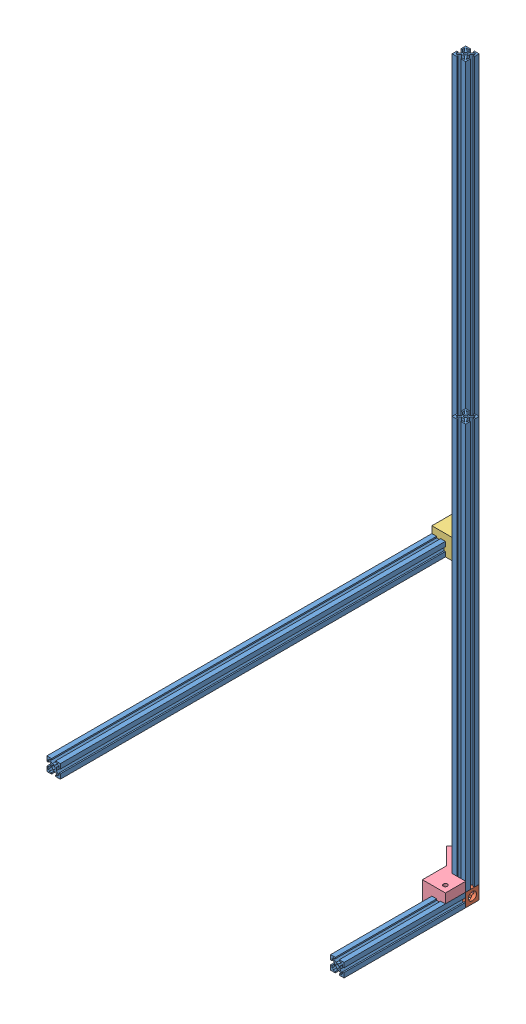
SolidWorks assembly Assem1, configuration Default. Lengths in mm.
Overall size (242.38 310 332.38).
9 component instances, 4 part files, 26 mates.
Components (placement in the parent):
- Makerbeam50-1000mm-1: Makerbeam50-1000mm [300mm] at (73.7272 153.9213 102.2524) size (10 10 300)
- MakerBeam-cube-1: MakerBeam-cube [Default] at (73.7272 153.9213 102.2524) x (-1 0 0) z (0 0 -1) size (10 10 10)
- Makerbeam50-1000mm-2: Makerbeam50-1000mm [300mm] at (73.7272 458.9213 97.2524) x (1 0 0) z (0 -1 0) size (10 10 300)
- ElectronicalMakerBeamBottomFix45-1: ElectronicalMakerBeamBottomFix45 [Default] at (78.7272 148.9213 92.2524) x (0 0 -1) z (0 1 0) size (25 35 15)
- Makerbeam50-1000mm-3: Makerbeam50-1000mm [300mm] at (84.8364 153.9213 105.4326) x (0.707107 0 -0.707107) z (0.707107 0 0.707107) size (10 10 300)
- ElectronicalMakerBeamBottomFix135-1: ElectronicalMakerBeamBottomFix135 [Default] at (221.1105 148.9213 234.6357) x (0 0 -1) z (0 1 0) size (42.68 29.7 17)
- Makerbeam50-1000mm-4: Makerbeam50-1000mm [90mm] at (306.1105 153.9213 334.6357) size (10 10 90)
- MakerBeam-cube-2: MakerBeam-cube [Default] at (301.1105 153.9213 329.6357) x (0 -1 0) z (1 0 0) size (10 10 10)
- Makerbeam50-1000mm-5: Makerbeam50-1000mm [300mm] at (306.1105 458.9213 329.6357) x (1 0 0) z (0 -1 0) size (10 10 300)
Mates (geometry in assembly coordinates):
- Coincident1: coincident anti-aligned: plane of Makerbeam50-1000mm-1 through (73.7272 153.9213 102.2524) normal (0 0 -1); plane of MakerBeam-cube-1 through (73.7272 153.9213 102.2524) normal (0 0 1)
- Coincident2: coincident aligned: plane of Makerbeam50-1000mm-1 through (78.7272 158.9213 402.2524) normal (1 0 0); plane of MakerBeam-cube-1 through (78.7272 148.9213 92.2524) normal (1 0 0)
- Coincident3: coincident aligned: plane of Makerbeam50-1000mm-1 through (68.7272 158.9213 402.2524) normal (0 1 0); plane of MakerBeam-cube-1 through (68.7272 158.9213 92.2524) normal (0 1 0)
- Coincident4: coincident anti-aligned: plane of MakerBeam-cube-1 through (68.7272 158.9213 92.2524) normal (0 1 0); plane of Makerbeam50-1000mm-2 through (73.7272 158.9213 97.2524) normal (0 -1 0)
- Coincident5: coincident aligned: plane of MakerBeam-cube-1 through (78.7272 148.9213 92.2524) normal (1 0 0); plane of Makerbeam50-1000mm-2 through (78.7272 158.9213 95.7524) normal (1 0 0)
- Coincident6: coincident aligned: plane of MakerBeam-cube-1 through (73.7272 153.9213 102.2524) normal (0 0 1); plane of Makerbeam50-1000mm-2 through (68.7272 158.9213 102.2524) normal (0 0 1)
- Coincident7: coincident anti-aligned: plane of Makerbeam50-1000mm-1 through (75.2272 158.9213 402.2524) normal (0 1 0); plane of ElectronicalMakerBeamBottomFix45-1 through (78.7272 158.9213 92.2524) normal (0 -1 0)
- Coincident8: coincident anti-aligned: plane of Makerbeam50-1000mm-1 through (78.7272 158.9213 402.2524) normal (1 0 0); plane of ElectronicalMakerBeamBottomFix45-1 through (78.7272 163.9213 92.2524) normal (-1 0 0)
- Coincident9: coincident anti-aligned: plane of Makerbeam50-1000mm-2 through (68.7272 158.9213 102.2524) normal (0 0 1); plane of ElectronicalMakerBeamBottomFix45-1 through (78.7272 163.9213 102.2524) normal (0 0 -1)
- Coincident10: coincident anti-aligned: plane of ElectronicalMakerBeamBottomFix45-1 through (88.3719 163.9213 101.8971) normal (0.707107 0 0.707107); plane of Makerbeam50-1000mm-3 through (84.8364 153.9213 105.4326) normal (-0.707107 0 -0.707107)
- Coincident11: coincident aligned: plane of ElectronicalMakerBeamBottomFix45-1 through (78.7272 163.9213 92.2524) normal (0.707107 0 -0.707107); plane of Makerbeam50-1000mm-3 through (300.5039 152.4213 314.0291) normal (0.707107 0 -0.707107)
- Coincident12: coincident aligned: plane of ElectronicalMakerBeamBottomFix45-1 through (78.7272 163.9213 92.2524) normal (0.707107 0 -0.707107); plane of Makerbeam50-1000mm-3 through (300.5039 152.4213 314.0291) normal (0.707107 0 -0.707107)
- Coincident13: coincident aligned: plane of ElectronicalMakerBeamBottomFix45-1 through (78.7272 163.9213 92.2524) normal (0.707107 0 -0.707107); plane of Makerbeam50-1000mm-3 through (300.5039 158.9213 314.0291) normal (0.707107 0 -0.707107)
- Coincident14: coincident anti-aligned: plane of ElectronicalMakerBeamBottomFix45-1 through (78.7272 158.9213 92.2524) normal (0 -1 0); plane of Makerbeam50-1000mm-3 through (298.0291 158.9213 316.504) normal (0 1 0)
- Coincident15: coincident anti-aligned: plane of Makerbeam50-1000mm-3 through (296.9684 153.9213 317.5646) normal (0.707107 0 0.707107); plane of ElectronicalMakerBeamBottomFix135-1 through (300.5039 148.9213 314.0291) normal (-0.707107 0 -0.707107)
- Coincident16: coincident aligned: plane of Makerbeam50-1000mm-3 through (300.5039 158.9213 314.0291) normal (0.707107 0 -0.707107); plane of ElectronicalMakerBeamBottomFix135-1 through (311.1105 165.9213 324.6357) normal (0.707107 0 -0.707107)
- Coincident17: coincident anti-aligned: plane of Makerbeam50-1000mm-3 through (298.0291 158.9213 316.504) normal (0 1 0); plane of ElectronicalMakerBeamBottomFix135-1 through (297.9937 158.9213 316.5393) normal (0 -1 0)
- Coincident18: coincident anti-aligned: plane of ElectronicalMakerBeamBottomFix135-1 through (311.1105 165.9213 324.6357) normal (0 0 1); plane of MakerBeam-cube-2 through (311.1105 148.9213 324.6357) normal (0 0 -1)
- Coincident19: coincident aligned: plane of ElectronicalMakerBeamBottomFix135-1 through (221.1105 148.9213 234.6357) normal (0 -1 0); plane of MakerBeam-cube-2 through (311.1105 148.9213 334.6357) normal (0 -1 0)
- Coincident20: coincident anti-aligned: plane of ElectronicalMakerBeamBottomFix135-1 through (301.1105 165.9213 324.6357) normal (1 0 0); plane of MakerBeam-cube-2 through (301.1105 153.9213 329.6357) normal (-1 0 0)
- Concentric1: concentric anti-aligned: cylinder of Makerbeam50-1000mm-4 through (306.1105 153.9213 424.6357) axis (0 0 -1) radius 1.25; cylinder of MakerBeam-cube-2 through (306.1105 153.9213 334.6357) axis (0 0 1) radius 1.25
- Coincident21: coincident aligned: plane of Makerbeam50-1000mm-4 through (311.1105 152.4213 424.6357) normal (1 0 0); plane of MakerBeam-cube-2 through (311.1105 153.9213 329.6357) normal (1 0 0)
- Coincident22: coincident anti-aligned: plane of Makerbeam50-1000mm-4 through (306.1105 153.9213 334.6357) normal (0 0 -1); plane of MakerBeam-cube-2 through (311.1105 148.9213 334.6357) normal (0 0 1)
- Concentric2: concentric anti-aligned: cylinder of MakerBeam-cube-2 through (306.1105 148.9213 329.6357) axis (0 -1 0) radius 1.25; cylinder of Makerbeam50-1000mm-5 through (306.1105 158.9213 329.6357) axis (0 1 0) radius 1.25
- Coincident23: coincident aligned: plane of MakerBeam-cube-2 through (311.1105 153.9213 329.6357) normal (1 0 0); plane of Makerbeam50-1000mm-5 through (311.1105 158.9213 334.6357) normal (1 0 0)
- Coincident24: coincident anti-aligned: plane of MakerBeam-cube-2 through (311.1105 158.9213 334.6357) normal (0 1 0); plane of Makerbeam50-1000mm-5 through (306.1105 158.9213 329.6357) normal (0 -1 0)
